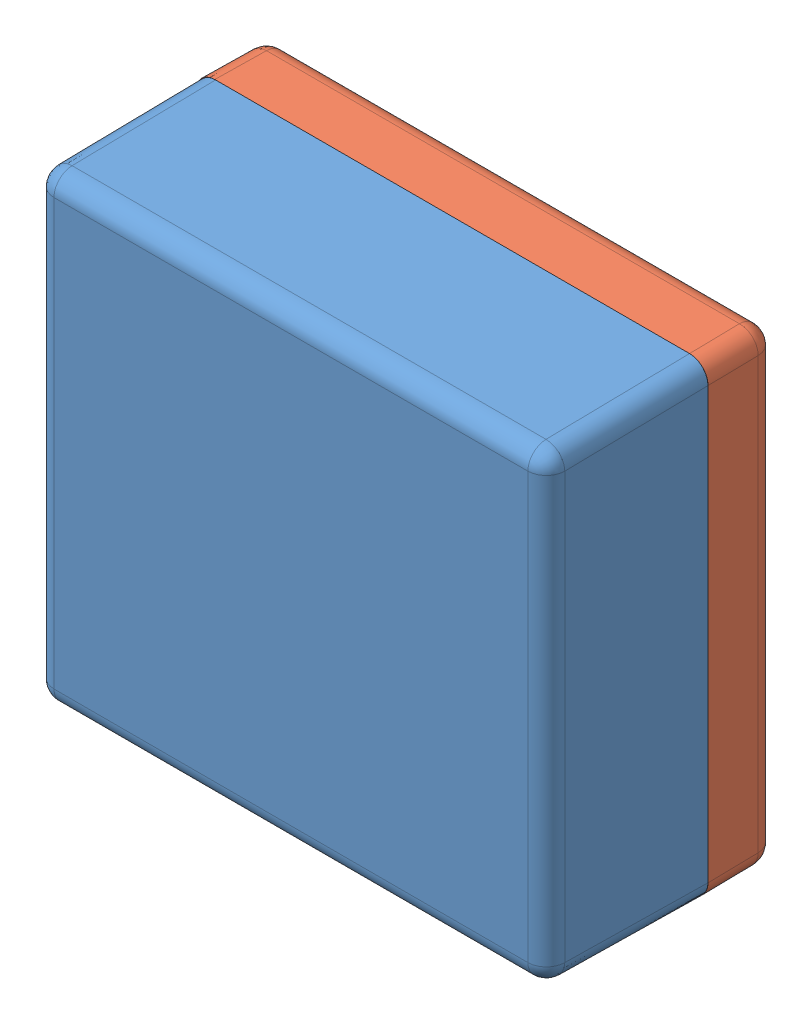
SolidWorks assembly Assem1, configuration Default. Lengths in mm.
Overall size (110.77 101.22 50).
2 component instances, 2 part files, 3 mates.
Components (placement in the parent):
- below part-1: below part [Default] at (-70.2324 -43.7689 -6.4145) size (110.6 101.22 37.01)
- Top Part-1: Top Part [Default] at (40.1058 56.8402 -6.4145) x (0 0 -1) z (-1 0 0) size (15.01 101.22 110.77)
Mates (geometry in assembly coordinates):
- Coincident1: coincident anti-aligned: plane of below part-1 through (-70.2324 -43.7689 -6.4145) normal (0 0 -1); plane of Top Part-1 through (-70.1442 56.8402 -6.4145) normal (0 0 1)
- Coincident5: coincident aligned: line of below part-1 through (-66.2324 -44.3798 -6.4145) axis (1 0 0); line of Top Part-1 through (-66.4054 -44.3798 -6.4145) axis (1 0 0)
- Coincident6: coincident aligned: line of below part-1 through (40.3676 -40.3792 -6.4145) axis (0 1 0); line of Top Part-1 through (40.3676 -40.3798 -6.4145) axis (0 1 0)
